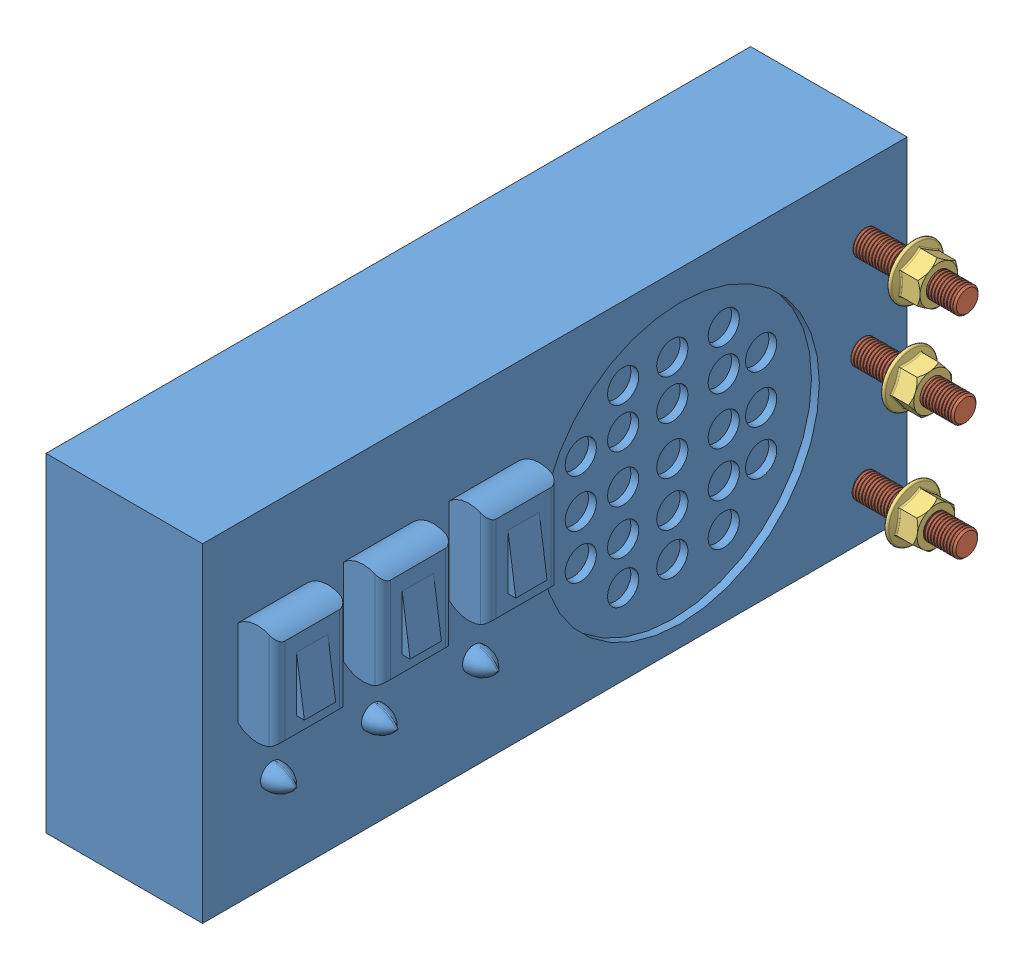
SolidWorks assembly Módulo Secundario, configuration Predeterminado. Lengths in mm.
Overall size (1380.85 775.26 781.89).
7 component instances, 3 part files, 6 mates.
Components (placement in the parent):
- Pieza2-1: Pieza2 [Predeterminado] at (86.3109 -135.8591 1253.8876) size (1360.37 775.26 781.89)
- heavy hex bolt_am-26: heavy hex bolt_am [B18.2.3.6M - Heavy hex bolt M16 x 2.0 x 70 --70S] at (170.5609 -75.7585 1055.5089) size (80.75 31.18 27)
- heavy hex bolt_am-27: heavy hex bolt_am [B18.2.3.6M - Heavy hex bolt M16 x 2.0 x 70 --70S] at (170.5609 -135.4779 1056.9234) size (80.75 31.18 27)
- heavy hex bolt_am-28: heavy hex bolt_am [B18.2.3.6M - Heavy hex bolt M16 x 2.0 x 70 --70S] at (171.3663 -209.3035 1056.6272) size (80.75 31.18 27)
- hex flange nut_am-16: hex flange nut_am [B18.2.2.4M - Hex flange nut, M16 x 2 --S] at (230.5252 -135.4779 1056.9234) x (0 -0.396181 -0.918173) z (1 0 0) size (34.5 34.5 16)
- hex flange nut_am-18: hex flange nut_am [B18.2.2.4M - Hex flange nut, M16 x 2 --S] at (233.1457 -75.7585 1055.5089) x (0 -0.03106 -0.999518) z (1 0 0) size (34.5 34.5 16)
- hex flange nut_am-19: hex flange nut_am [B18.2.2.4M - Hex flange nut, M16 x 2 --S] at (232.3867 -209.3035 1056.6272) x (0 -0.181723 -0.98335) z (1 0 0) size (34.5 34.5 16)
Mates (geometry in assembly coordinates):
- Coincidente31: coincident: circle of heavy hex bolt_am-28; plane of heavy hex bolt_am-28 through (182.1163 -193.7151 1056.6272) normal (1 0 0)
- Coincidente33: coincident: plane of Pieza2-1 through (181.3109 -138.7779 1173.8876) normal (1 0 0); plane of heavy hex bolt_am-27 through (181.3109 -119.8894 1056.9234) normal (1 0 0)
- Coincidente34: coincident: plane of Pieza2-1 through (181.3109 -138.7779 1173.8876) normal (1 0 0); plane of heavy hex bolt_am-26 through (181.3109 -60.1701 1055.5089) normal (1 0 0)
- Concéntrica13: concentric aligned: circle of heavy hex bolt_am-26; circle of hex flange nut_am-18
- Concéntrica14: concentric aligned: circle of heavy hex bolt_am-27; circle of hex flange nut_am-16
- Concéntrica15: concentric aligned: circle of heavy hex bolt_am-28; circle of hex flange nut_am-19
